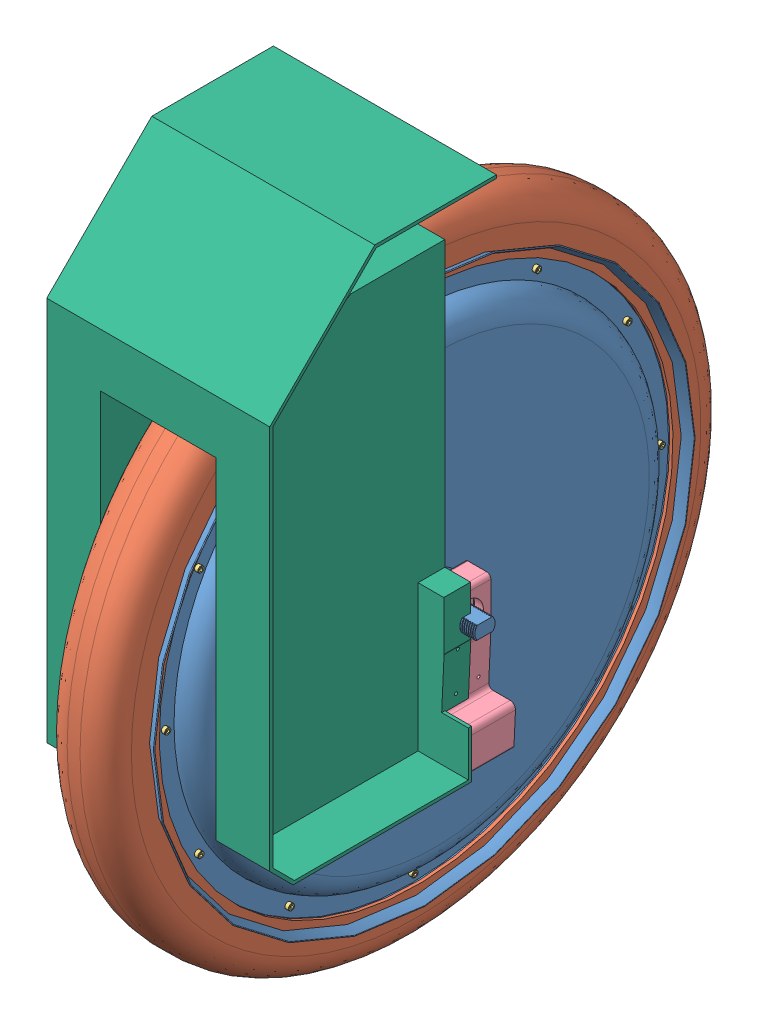
SolidWorks assembly euc0.3, configuration Default. Lengths in mm.
Overall size (364.75 810.04 810.04).
36 component instances, 10 part files, 23 mates.
Components (placement in the parent):
- wheel-1: wheel [Default] at origin size (217.51 810.04 810.04)
  - motor-1: motor [Default] at origin size (188.73 505.83 505.83)
  - tyre-1: tyre [Default] at (-29.8207 0 0) x (1 0 0) z (0 0.587098 0.809516) size (60 580 580)
  - socket head cap screw_ai-1: socket head cap screw_ai [HX-SHCS 0.138-40x0.188x0.188-N] at (29.5052 231 0) x (-1 0 0) z (0 0 -1) size (8.28 5.74 5.74)
  - socket head cap screw_ai-2: socket head cap screw_ai [HX-SHCS 0.138-40x0.188x0.188-N] at (29.5052 200.0519 -115.5) x (-1 0 0) z (0 -0.5 -0.866025) size (8.28 5.74 5.74)
  - socket head cap screw_ai-3: socket head cap screw_ai [HX-SHCS 0.138-40x0.188x0.188-N] at (29.5052 200.0519 115.5) x (-1 0 0) z (0 0.5 -0.866025) size (8.28 5.74 5.74)
  - socket head cap screw_ai-4: socket head cap screw_ai [HX-SHCS 0.138-40x0.188x0.188-N] at (29.5052 115.5 200.0519) x (-1 0 0) z (0 0.866025 -0.5) size (8.28 5.74 5.74)
  - socket head cap screw_ai-5: socket head cap screw_ai [HX-SHCS 0.138-40x0.188x0.188-N] at (29.5052 0 231) x (-1 0 0) z (0 1 0) size (8.28 5.74 5.74)
  - socket head cap screw_ai-6: socket head cap screw_ai [HX-SHCS 0.138-40x0.188x0.188-N] at (29.5052 -115.5 200.0519) x (-1 0 0) z (0 0.866025 0.5) size (8.28 5.74 5.74)
  - socket head cap screw_ai-7: socket head cap screw_ai [HX-SHCS 0.138-40x0.188x0.188-N] at (29.5052 -200.0519 115.5) x (-1 0 0) z (0 0.5 0.866025) size (8.28 5.74 5.74)
  - socket head cap screw_ai-8: socket head cap screw_ai [HX-SHCS 0.138-40x0.188x0.188-N] at (29.5052 -231 0) x (-1 0 0) z (0 0 1) size (8.28 5.74 5.74)
  - socket head cap screw_ai-9: socket head cap screw_ai [HX-SHCS 0.138-40x0.188x0.188-N] at (29.5052 -200.0519 -115.5) x (-1 0 0) z (0 -0.5 0.866025) size (8.28 5.74 5.74)
  - socket head cap screw_ai-10: socket head cap screw_ai [HX-SHCS 0.138-40x0.188x0.188-N] at (29.5052 -115.5 -200.0519) x (-1 0 0) z (0 -0.866025 0.5) size (8.28 5.74 5.74)
  - socket head cap screw_ai-11: socket head cap screw_ai [HX-SHCS 0.138-40x0.188x0.188-N] at (29.5052 0 -231) x (-1 0 0) z (0 -1 0) size (8.28 5.74 5.74)
  - socket head cap screw_ai-12: socket head cap screw_ai [HX-SHCS 0.138-40x0.188x0.188-N] at (29.5052 115.5 -200.0519) x (-1 0 0) z (0 -0.866025 -0.5) size (8.28 5.74 5.74)
  - socket head cap screw_ai-13: socket head cap screw_ai [HX-SHCS 0.138-40x0.188x0.188-N] at (-29.5052 231 0) size (8.28 5.74 5.74)
  - socket head cap screw_ai-14: socket head cap screw_ai [HX-SHCS 0.138-40x0.188x0.188-N] at (-29.5052 200.0519 -115.5) x (1 0 0) z (0 0.5 0.866025) size (8.28 5.74 5.74)
  - socket head cap screw_ai-15: socket head cap screw_ai [HX-SHCS 0.138-40x0.188x0.188-N] at (-29.5052 200.0519 115.5) x (1 0 0) z (0 -0.5 0.866025) size (8.28 5.74 5.74)
  - socket head cap screw_ai-16: socket head cap screw_ai [HX-SHCS 0.138-40x0.188x0.188-N] at (-29.5052 115.5 200.0519) x (1 0 0) z (0 -0.866025 0.5) size (8.28 5.74 5.74)
  - socket head cap screw_ai-17: socket head cap screw_ai [HX-SHCS 0.138-40x0.188x0.188-N] at (-29.5052 0 231) x (1 0 0) z (0 -1 0) size (8.28 5.74 5.74)
  - socket head cap screw_ai-18: socket head cap screw_ai [HX-SHCS 0.138-40x0.188x0.188-N] at (-29.5052 -115.5 200.0519) x (1 0 0) z (0 -0.866025 -0.5) size (8.28 5.74 5.74)
  - socket head cap screw_ai-19: socket head cap screw_ai [HX-SHCS 0.138-40x0.188x0.188-N] at (-29.5052 -200.0519 115.5) x (1 0 0) z (0 -0.5 -0.866025) size (8.28 5.74 5.74)
  - socket head cap screw_ai-20: socket head cap screw_ai [HX-SHCS 0.138-40x0.188x0.188-N] at (-29.5052 -231 0) x (1 0 0) z (0 0 -1) size (8.28 5.74 5.74)
  - socket head cap screw_ai-21: socket head cap screw_ai [HX-SHCS 0.138-40x0.188x0.188-N] at (-29.5052 -200.0519 -115.5) x (1 0 0) z (0 0.5 -0.866025) size (8.28 5.74 5.74)
  - socket head cap screw_ai-22: socket head cap screw_ai [HX-SHCS 0.138-40x0.188x0.188-N] at (-29.5052 -115.5 -200.0519) x (1 0 0) z (0 0.866025 -0.5) size (8.28 5.74 5.74)
  - socket head cap screw_ai-23: socket head cap screw_ai [HX-SHCS 0.138-40x0.188x0.188-N] at (-29.5052 0 -231) x (1 0 0) z (0 1 0) size (8.28 5.74 5.74)
  - socket head cap screw_ai-24: socket head cap screw_ai [HX-SHCS 0.138-40x0.188x0.188-N] at (-29.5052 115.5 -200.0519) x (1 0 0) z (0 0.866025 0.5) size (8.28 5.74 5.74)
  - pedal hanger1-1: pedal hanger1 [Default] at (128.9328 -140.4403 -75.0082) x (0.997537 -0.070149 0) z (-0.006861 -0.09757 0.995205) size (54.31 133.41 56.48)
  - pedal hanger2-1: pedal hanger2 [Default] at (-128.9328 -140.4403 75.0082) x (-0.997537 -0.070149 0) z (0.006861 -0.09757 -0.995205) size (54.31 133.41 56.48)
- mt60 fem-1: mt60 fem [Default] at (85.5155 -2.714 -4.2673) x (0 1 0) z (0.866025 0 -0.5) size (29 12 12.94) (hidden)
  - Мама^mt60 fem-1: Мама^mt60 fem [По умолчанию] at (18.214 0 0) x (0 0 -1) z (1 0 0) size (12.94 12 20) (virtual)
  - Колпачек 2^mt60 fem-1: Колпачек 2^mt60 fem [По умолчанию] at (35.714 0 0) x (0 0 -1) z (1 0 0) size (12.94 12 13) (virtual)
  - Деталь11^mt60 fem-1: Деталь11^mt60 fem [По умолчанию] at (44.714 0 0) x (0 0 -1) z (1 0 0) size (8 7.46 6.5) (virtual)
- Chassis^euc0.3-1: Chassis^euc0.3 [Default] at (-0.156 -3.3601 -11.33) size (208.31 479.6 211.72) (virtual)
  - Internal chassis^Chassis_euc0.3-1: Internal chassis^Chassis_euc0.3 [Default] at origin size (208.31 479.6 211.72) (virtual)
  - Lid^Chassis_euc0.3-1: Lid^Chassis_euc0.3 [Default] at (0.156 3.3601 11.33) (virtual)
Mates (geometry in assembly coordinates):
- Lock1: lock: unknown of wheel-1/pedal hanger1-1; unknown of Chassis-1/Internal chassis-1
- Parallel1: parallel anti-aligned: plane of Chassis-1/Internal chassis-1 through (0 28 0) normal (0 1 0); plane of mt60 fem-1/Copy of Мама^mt60 fem-1 through (90.0311 15.5 3.5538) normal (0 -1 0)
- Parallel2: parallel aligned: plane of Chassis-1/Internal chassis-1 through (57 28 288) normal (1 0 0); plane of mt60 fem-1/Copy of Мама^mt60 fem-1 through (93 29 3.5538) normal (1 0 0)
- Coincident3: coincident anti-aligned: plane of Chassis-1/Internal chassis-1 through (93 7.266 3.5) normal (-1 0 0); plane of mt60 fem-1/Copy of Мама^mt60 fem-1 through (93 29 3.5538) normal (1 0 0)
- Coincident4: coincident anti-aligned: plane of Chassis-1/Internal chassis-1 through (82.4378 7.266 2.5981) normal (0.5 0 -0.866025); plane of mt60 fem-1/Copy of Мама^mt60 fem-1 through (82.4845 29 2.625) normal (-0.5 0 0.866025)
- Coincident5: coincident aligned: plane of Chassis-1/Internal chassis-1 through (100 25 0) normal (0 -1 0); plane of mt60 fem-1/Copy of Мама^mt60 fem-1 through (83.9689 25 0.0538) normal (0 -1 0)
- Coincident18: coincident anti-aligned: plane of Chassis-1/Internal chassis-1 through (57 28 288) normal (1 0 0); plane of Battery1-1 through (57 187.8877 190.3024) normal (-1 0 0)
- Coincident23: coincident anti-aligned: plane of Chassis-1/Internal chassis-1 through (57 28 288) normal (1 0 0); plane of Battery2-2 through (57 212.7697 -24.9641) normal (-1 0 0)
- Parallel5: parallel aligned: plane of Chassis-1/Internal chassis-1 through (0 28 0) normal (0 1 0); plane of Battery1-1 through (75 187.8877 109.3024) normal (0 1 0)
- Parallel6: parallel aligned: plane of Chassis-1/Internal chassis-1 through (0 28 0) normal (0 1 0); plane of Battery2-2 through (75 212.7697 -105.9641) normal (0 1 0)
- InPlace2: in place: plane of ? through (57 28 288) normal (1 0 0); plane of ? through (57 0 0) normal (1 0 0); moOrthogonalPlaneRef_w of ? through (57 28 288) normal (1 0 0); plane of ? through (57 0 0) normal (0 1 0); plane of ? through (57 28 288) normal (1 0 0); plane of ? through (57 0 0) normal (0 0 -1); plane of ? through (57 28 288) normal (1 0 0); unknown of ?
- Coincident26: coincident aligned: plane of ?; plane of ?
- Coincident27: coincident aligned: moOrthogonalPlaneRef_w of Chassis-1/Internal chassis-1 through (57 0 0) normal (0 1 0); plane of Lid^euc0.2-2 through (57 0 0) normal (0 1 0)
- Coincident28: coincident anti-aligned: moOrthogonalPlaneRef_w of Chassis-1/Internal chassis-1 through (57 0 0) normal (0 0 1); plane of Lid^euc0.2-2 through (57 0 0) normal (0 0 -1)
- InPlace3: in place: plane of ? through (0 303.0294 0) normal (0 1 0); plane of ? through (0 303.0294 0) normal (0 1 0); plane of ? through (0 303.0294 0) normal (0 1 0); plane of ? through (0 303.0294 0) normal (0 0 -1); plane of ? through (0 303.0294 0) normal (0 1 0); plane of ? through (0 303.0294 0) normal (1 0 0); plane of ? through (0 303.0294 0) normal (0 1 0); unknown of ?
- Coincident1482: coincident aligned: plane of ?; plane of ?
- Coincident1483: coincident aligned: moOrthogonalPlaneRef_w of top chassis^euc0.2-1 through (0 303.0294 0) normal (0 0 -1); plane of Pcb plate^euc0.2-1 through (0 303.0294 0) normal (0 0 -1)
- Coincident1484: coincident anti-aligned: moOrthogonalPlaneRef_w of top chassis^euc0.2-1 through (0 303.0294 0) normal (-1 0 0); plane of Pcb plate^euc0.2-1 through (0 303.0294 0) normal (1 0 0)
- Coincident1488: coincident anti-aligned: plane of Pcb plate^euc0.2-1 through (-24 312.0294 76) normal (0 1 0); plane of pcb^euc0.2-1 through (0 312.0294 0) normal (0 -1 0)
- Coincident1489: coincident aligned: plane of Pcb plate^euc0.2-1 through (-40 307.0294 80) normal (0 0 1); plane of pcb^euc0.2-1 through (-28 315.0294 80) normal (0 0 1)
- Coincident1490: coincident anti-aligned: plane of Pcb plate^euc0.2-1 through (28 315.0294 -80) normal (-1 0 0); plane of pcb^euc0.2-1 through (28 315.0294 80) normal (1 0 0)
- Coincident1491: coincident anti-aligned: plane of Chassis-1/Internal chassis-1 through (57 28 288) normal (1 0 0); plane of Battery-2 through (57 183.6915 -26.6601) normal (-1 0 0)
- Coincident1492: coincident anti-aligned: plane of wheel-1/pedal hanger1-1 through (78 -21 22) normal (0.998924 -0.046379 0); plane of Chassis^euc0.3-1/Internal chassis^Chassis_euc0.3-1 through (78.6491 -7.0189 -11.33) normal (-0.998924 0.046379 0)
